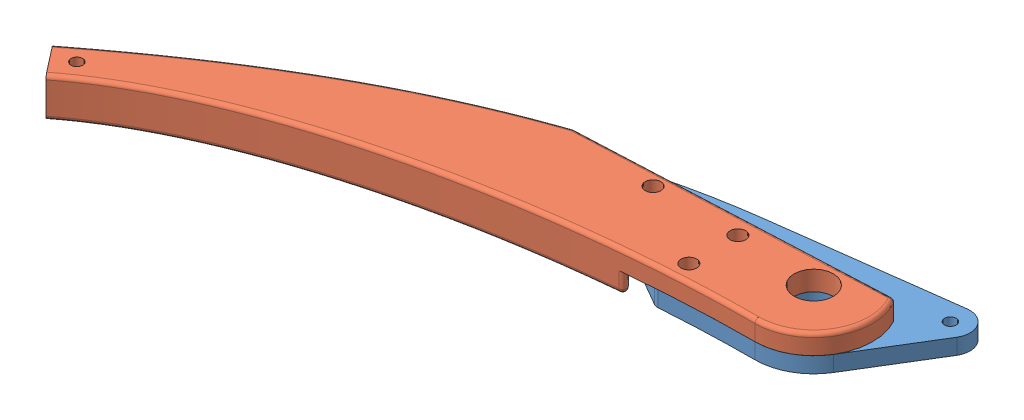
SolidWorks assembly leg_lower_new, configuration Default. Lengths in mm.
Overall size (175.71 22.31 79.4).
2 component instances, 2 part files, 3 mates.
Components (placement in the parent):
- leg_lower_plate-1: leg_lower_plate [Default] at (140.9521 79.4022 117.1717) size (84.41 4 35.22)
- leg_lower - Copy-1: leg_lower - Copy [Default] at (140.9521 78.4022 117.1717) size (165.23 22.31 67.7)
Mates (geometry in assembly coordinates):
- Concentric1: concentric aligned: cylinder of leg_lower - Copy-1 through (140.9521 78.4022 117.1717) axis (0 1 0) radius 5.1; cylinder of leg_lower_plate-1 through (140.9521 73.4022 117.1717) axis (0 1 0) radius 5
- Coincident2: coincident anti-aligned: plane of leg_lower - Copy-1 through (140.9521 83.4022 117.1717) normal (0 -1 0); plane of leg_lower_plate-1 through (140.9521 83.4022 117.1717) normal (0 1 0)
- Parallel1: parallel anti-aligned: plane of leg_lower - Copy-1 through (111.7411 83.4022 133.4716) normal (0.5 0 -0.866025); plane of leg_lower_plate-1 through (79.022 79.4022 111.4385) normal (-0.5 0 0.866025)
